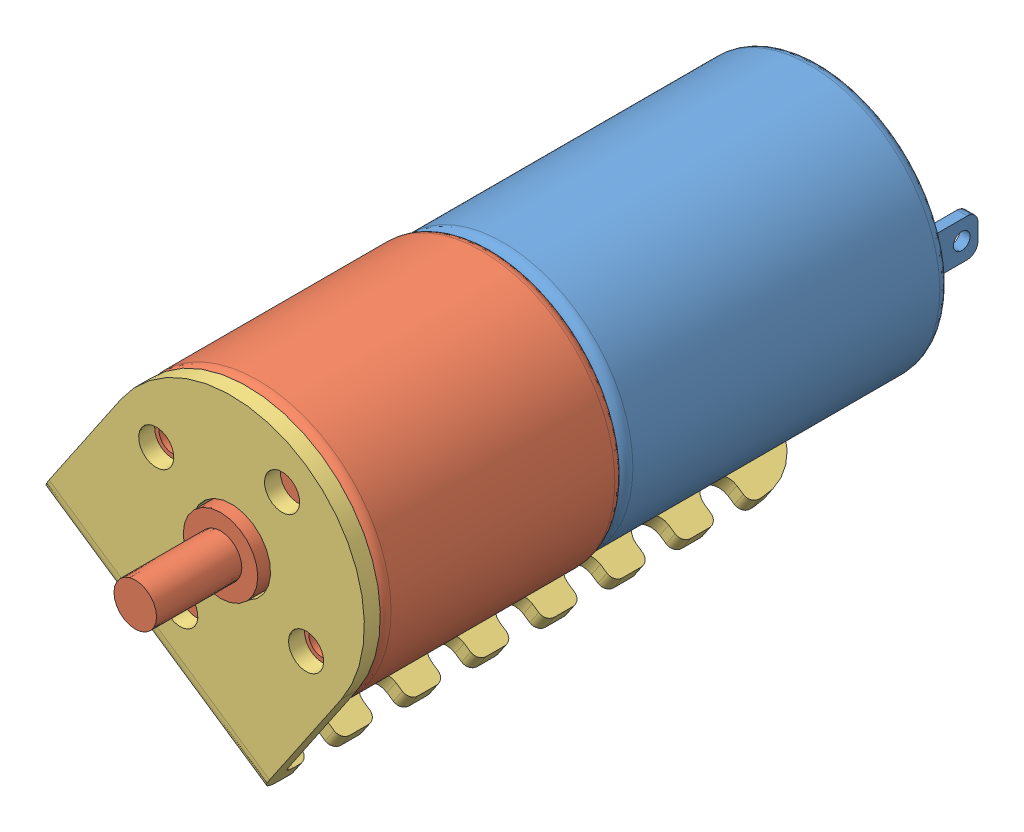
SolidWorks assembly Motor_com_suporte, configuration Valor predeterminado. Lengths in mm.
Overall size (35.57 35.97 69.3).
4 component instances, 3 part files, 3 mates.
Components (placement in the parent):
- Motor-2: Motor [Valor predeterminado] at (3.672 0.435 -26.0477) size (25 25 69.3)
  - Motor-1: Motor [Valor predeterminado] at (-6.4714 0.7429 0) size (24.4 24.4 45.8)
  - Motor_Redutor-1: Motor_Redutor [Valor predeterminado] at (-6.4714 0.7429 30.8) size (25 25 33.5)
- Suporte_Motor-1: Suporte_Motor [Valor predeterminado] at (-21.0049 -3.3839 29.2523) x (0.827349 -0.561689 0) z (0 0 1) size (25 26.5 51.5)
Mates (geometry in assembly coordinates):
- Concêntrico1: concentric anti-aligned: cylinder of Motor-2/Motor_Redutor-1 through (-2.7994 1.1779 30.2523) axis (0 0 -1) radius 3.5; cylinder of Suporte_Motor-1 through (-2.7994 1.1779 4.2523) axis (0 0 1) radius 3.7
- Coincidente1: coincident anti-aligned: plane of Motor-2/Motor_Redutor-1 through (-2.7994 1.1779 27.7523) normal (0 0 1); plane of Suporte_Motor-1 through (-6.1202 18.5409 27.7523) normal (0 0 -1)
- Concêntrico2: concentric aligned: cylinder of Motor-2/Motor_Redutor-1 through (4.233 -3.5965 27.7523) axis (0 0 1) radius 1.25; cylinder of Suporte_Motor-1 through (4.233 -3.5965 4.2523) axis (0 0 1) radius 1.65
